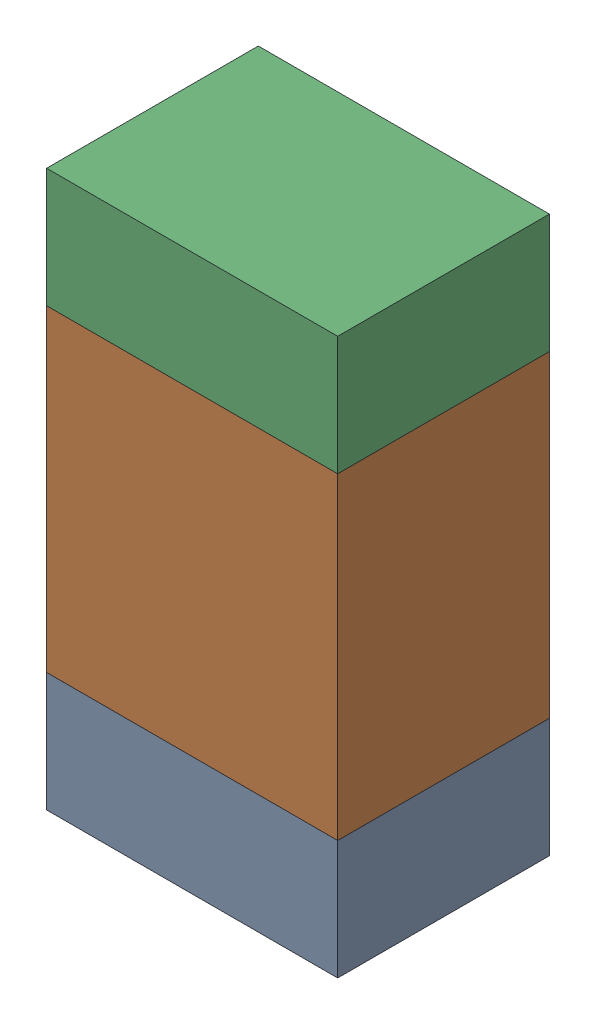
SolidWorks assembly R312_1PCB, configuration Default. Lengths in mm.
Overall size (0.55 1.05 0.4).
6 component instances, 2 part files, 0 mates.
Components (placement in the parent):
- 846483288-1: 846483288 [Default] at (125.0344 113.0374 -2.0638) size (0.55 0.22 0.4)
  - Extruded_12-1: Extruded_12 [Default] at origin size (0.55 0.22 0.4)
- 846483424-1: 846483424 [Default] at (125.0344 113.4499 -2.0638) size (0.55 0.6 0.4)
  - Extruded_13-1: Extruded_13 [Default] at origin size (0.55 0.6 0.4)
- 846483288-2: 846483288 [Default] at (125.0344 113.8624 -2.0638) size (0.55 0.22 0.4)
  - Extruded_12-1: Extruded_12 [Default] at origin size (0.55 0.22 0.4)
